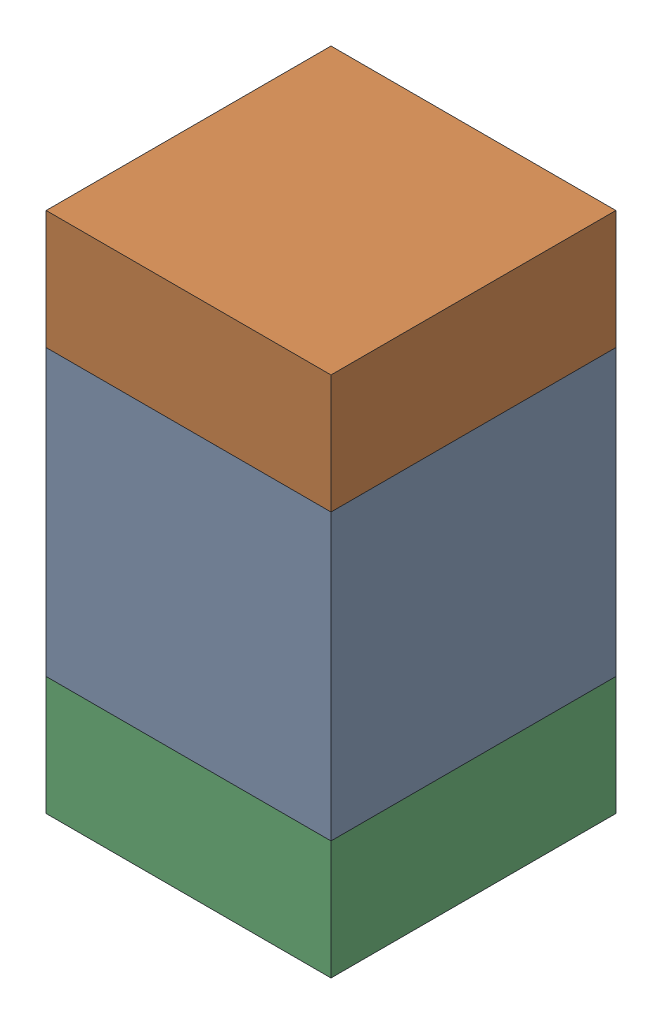
SolidWorks assembly C109_2PCB, configuration Default. Lengths in mm.
Overall size (0.6 1.1 0.6).
6 component instances, 2 part files, 0 mates.
Components (placement in the parent):
- 761606048-1: 761606048 [Default] at (116.7 89.8 0) size (0.6 0.6 0.6)
  - Extruded_9-1: Extruded_9 [Default] at origin size (0.6 0.6 0.6)
- 854785296-1: 854785296 [Default] at (116.7 90.225 0) size (0.6 0.25 0.6)
  - Extruded_10-1: Extruded_10 [Default] at origin size (0.6 0.25 0.6)
- 854785296-2: 854785296 [Default] at (116.7 89.375 0) size (0.6 0.25 0.6)
  - Extruded_10-1: Extruded_10 [Default] at origin size (0.6 0.25 0.6)
